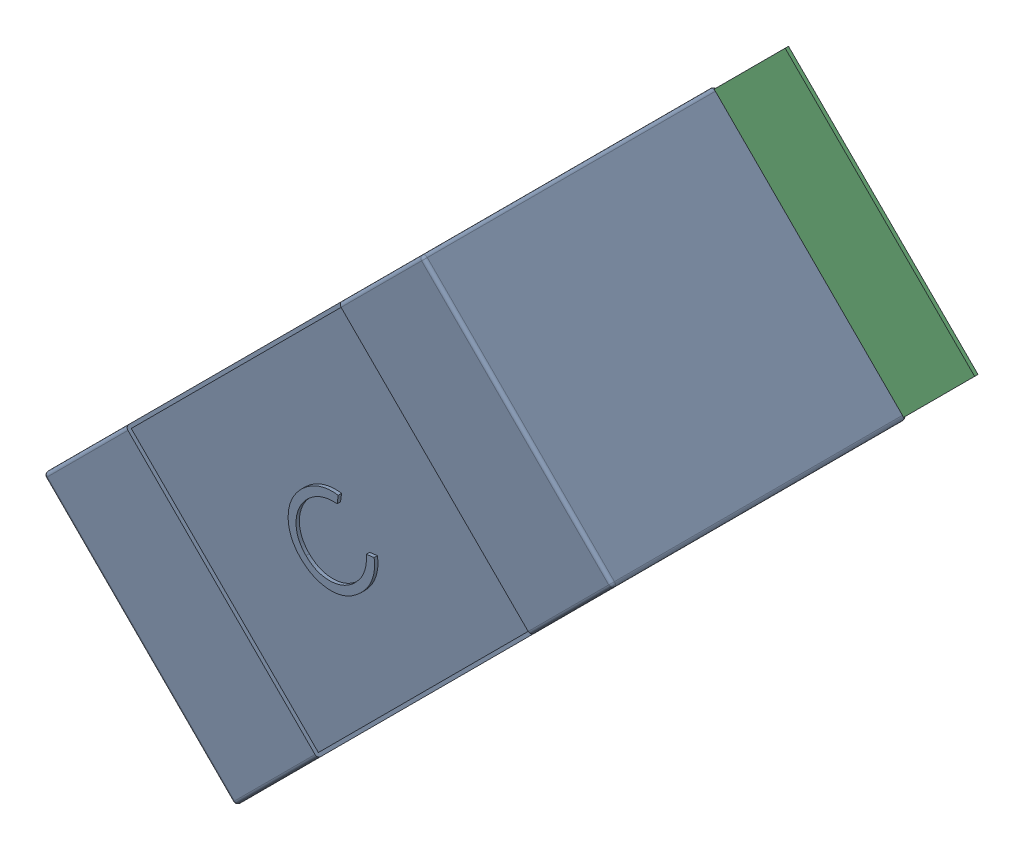
SolidWorks assembly C55, configuration Défaut. Lengths in mm.
Overall size (2.12 2.12 0.88).
5 component instances, 2 part files, 0 mates.
Components (placement in the parent):
- 0603_C-1: 0603_C [Défaut] at (66.9302 -32.8834 0) x (0.707107 0.707107 0) z (0 0 1) size (1.6 0.81 0.88)
- 8260086064-1: 8260086064 [Défaut] at (66.6863 -33.1273 0) size (0.99 0.99 0.01)
  - Extruded_132-1: Extruded_132 [Défaut] at origin size (0.99 0.99 0.01)
- 8260086064-2: 8260086064 [Défaut] at (67.8141 -31.9995 0) size (0.99 0.99 0.01)
  - Extruded_132-1: Extruded_132 [Défaut] at origin size (0.99 0.99 0.01)
